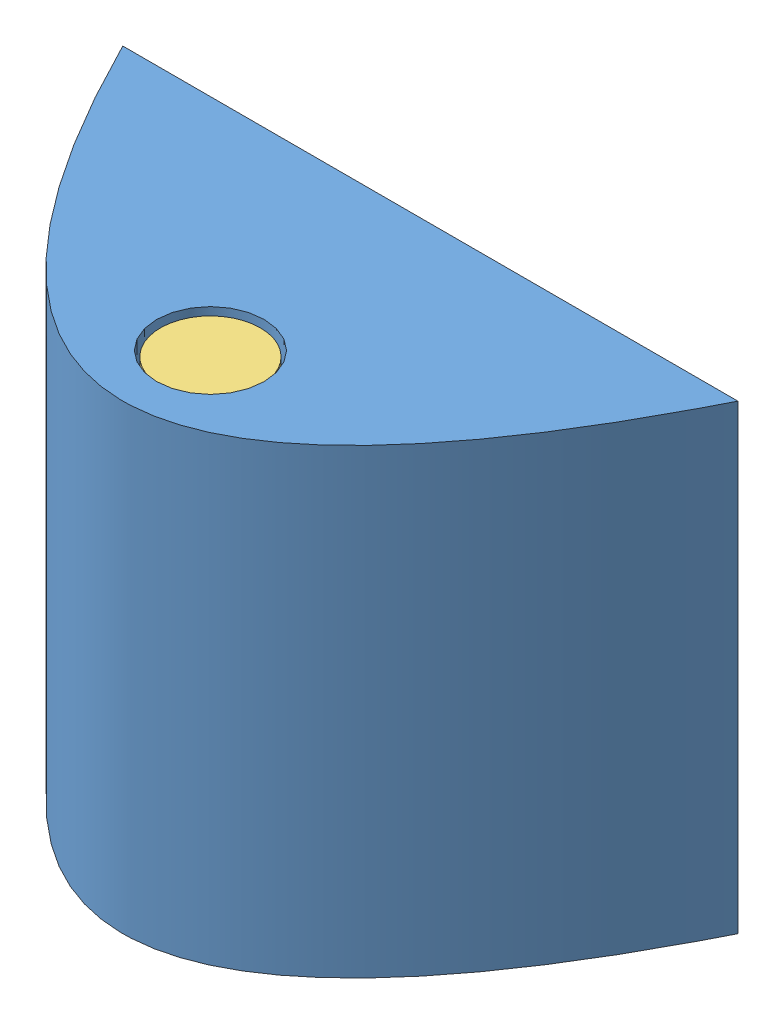
SolidWorks assembly Assem1, configuration Default. Lengths in mm.
Overall size (400 300 400).
4 component instances, 3 part files, 7 mates.
Components (placement in the parent):
- boat-1: boat [Default] at origin size (400 300 400)
- Ballast-2: Ballast [Default] at (0 127 143) size (31.5 46 31.5)
- can-1: can [Default] at (0 173 143) size (65 123.5 65)
- can-2: can [Default] at (0 3.5 143) size (65 123.5 65)
Mates (geometry in assembly coordinates):
- Coincident1: coincident aligned: plane of boat-1 through (187.4797 302.0265 484.0497) normal (0 1 0); plane of Ballast-2 through (187.4797 302.0265 484.0497) normal (0 1 0)
- Concentric1: concentric aligned: circle of boat-1; circle of Ballast-2
- Coincident2: coincident anti-aligned: plane of boat-1 through (187.4797 256.0265 484.0497) normal (0 -1 0); plane of can-2 through (187.4797 256.0265 484.0497) normal (0 1 0)
- Concentric2: concentric aligned: circle of boat-1; circle of can-2
- Coincident3: coincident anti-aligned: plane of boat-1 through (187.4797 302.0265 484.0497) normal (0 1 0); plane of can-1 through (187.4797 302.0265 484.0497) normal (0 -1 0)
- Concentric3: concentric aligned: circle of boat-1; circle of can-1
- Coincident5: coordinate: point of boat-1; point of assembly
